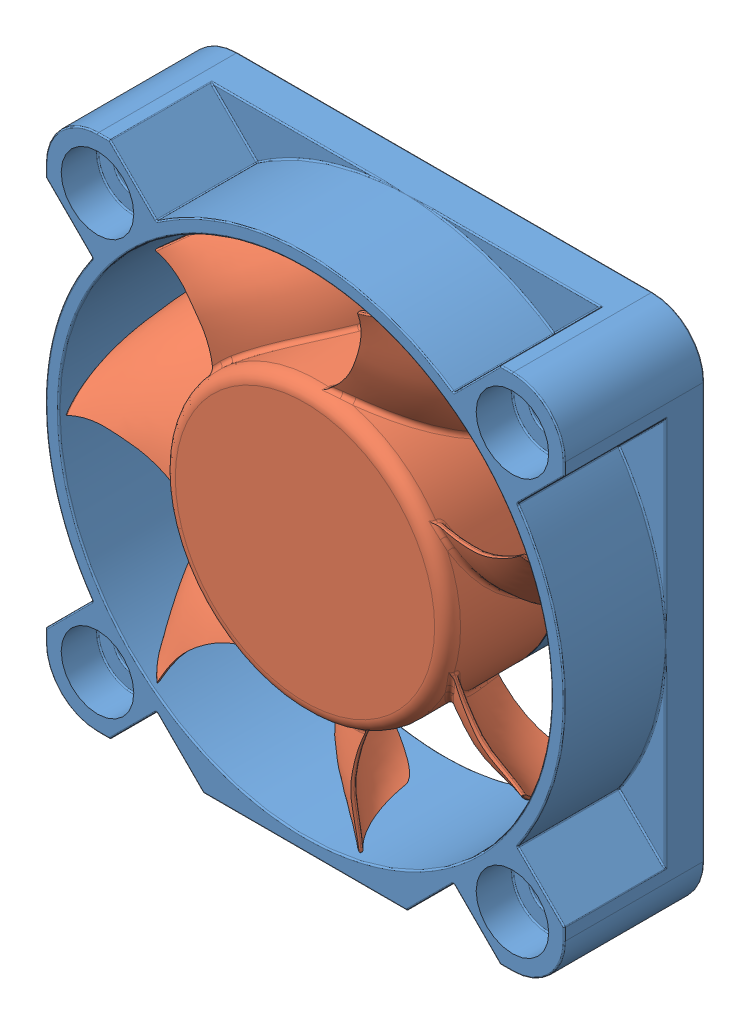
SolidWorks assembly Fan, configuration Default. Lengths in mm.
Overall size (42.57 44.74 10.81).
2 component instances, 2 part files, 0 mates.
Components (placement in the parent):
- CPU - -KF0410-01-PLASTIC CASING-1: CPU - -KF0410-01-PLASTIC CASING [Default] at (0.9289 7.0036 0) size (42.57 44.74 10.81)
- CPU - -KF0410-01- PLASTIC ROTOR-1: CPU - -KF0410-01- PLASTIC ROTOR [Default] at (0.9289 7.0036 -1) size (37.39 37 9.12)
